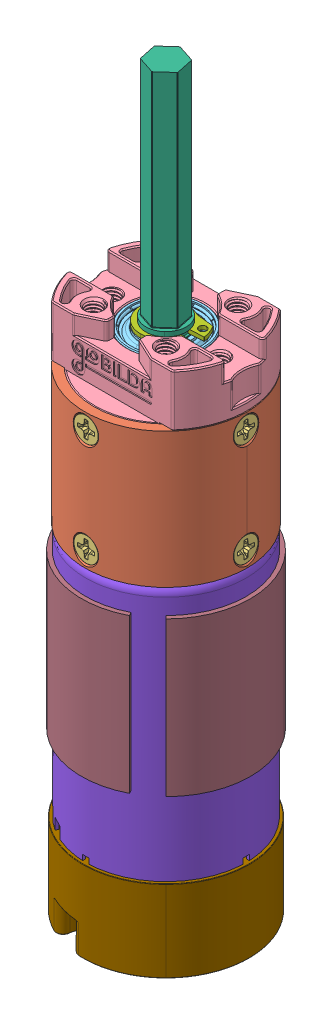
SolidWorks assembly Rex shaft 435rpm motor 45mm length, configuration Default. Lengths in mm.
Overall size (52.29 163.72 52.29).
30 component instances, 15 part files, 0 mates.
Components (placement in the parent):
- 5204-8002-0014 assembly.STEP-1: 5204-8002-0014 assembly.STEP [Default] at origin size (52.29 196.05 52.29)
  - 5104-8002-0014 Simple.STEP-1: 5104-8002-0014 Simple.STEP [Default] at (21.5499 39.1 -25.8711) size (36 121.1 35.97)
    - 5103 Gearbox Base.STEP-1: 5103 Gearbox Base.STEP [Default] at (-58.7206 21.0354 14.7927) size (31.91 5.69 31.91)
    - 5103 Gearbox Barrel (2 stage, simple)_Gear Blank.STEP-1: 5103 Gearbox Barrel (2 stage, simple)_Gear Blank.STEP [Default] at (-58.7206 64.0354 14.7927) x (1 0 0) z (0 -1 0) size (35.97 35.97 30)
    - 5103 Gearbox Barrel Screw (M3 x 8mm length Flat Head)_92010A118.STEP-1: 5103 Gearbox Barrel Screw (M3 x 8mm length Flat Head)_92010A118.STEP [Default] at (-58.7206 24.5354 30.8757) x (0.002439 -0.999997 0) z (0 0 1) size (5.46 5.46 8)
    - 5103 Gearbox Barrel Screw (M3 x 8mm length Flat Head)_92010A118.STEP-2: 5103 Gearbox Barrel Screw (M3 x 8mm length Flat Head)_92010A118.STEP [Default] at (-58.7206 47.5354 30.8757) x (-0.002439 -0.999997 0) z (0 0 1) size (5.46 5.46 8)
    - 5103 Gearbox Barrel Screw (M3 x 8mm length Flat Head)_92010A118.STEP-3: 5103 Gearbox Barrel Screw (M3 x 8mm length Flat Head)_92010A118.STEP [Default] at (-42.6376 24.5354 14.7927) x (0 -0.999997 -0.002439) z (1 0 0) size (5.46 5.46 8)
    - 5103 Gearbox Barrel Screw (M3 x 8mm length Flat Head)_92010A118.STEP-4: 5103 Gearbox Barrel Screw (M3 x 8mm length Flat Head)_92010A118.STEP [Default] at (-58.7206 24.5354 -1.2903) x (-0.002439 -0.999997 0) z (0 0 -1) size (5.46 5.46 8)
    - 5103 Gearbox Barrel Screw (M3 x 8mm length Flat Head)_92010A118.STEP-5: 5103 Gearbox Barrel Screw (M3 x 8mm length Flat Head)_92010A118.STEP [Default] at (-74.8037 24.5354 14.7927) x (0 -0.999997 0.002439) z (-1 0 0) size (5.46 5.46 8)
    - 5103 Gearbox Barrel Screw (M3 x 8mm length Flat Head)_92010A118.STEP-6: 5103 Gearbox Barrel Screw (M3 x 8mm length Flat Head)_92010A118.STEP [Default] at (-42.6376 47.5354 14.7927) x (0 -0.999997 0.002439) z (1 0 0) size (5.46 5.46 8)
    - 5103 Gearbox Barrel Screw (M3 x 8mm length Flat Head)_92010A118.STEP-7: 5103 Gearbox Barrel Screw (M3 x 8mm length Flat Head)_92010A118.STEP [Default] at (-58.7206 47.5354 -1.2903) x (0.002439 -0.999997 0) z (0 0 -1) size (5.46 5.46 8)
    - 5103 Gearbox Barrel Screw (M3 x 8mm length Flat Head)_92010A118.STEP-8: 5103 Gearbox Barrel Screw (M3 x 8mm length Flat Head)_92010A118.STEP [Default] at (-74.8037 47.5354 14.7927) x (0 -0.999997 -0.002439) z (-1 0 0) size (5.46 5.46 8)
    - 5103 Gearbox Face.STEP-1: 5103 Gearbox Face.STEP [Default] at (-58.7206 45.5354 14.7927) size (36 17.1 31.91)
    - 5103 Gearbox Bearing.STEP-1: 5103 Gearbox Bearing.STEP [Default] at (-58.7206 53.6354 14.7927) size (17 5 17)
    - 5103 Gearbox Bearing.STEP-2: 5103 Gearbox Bearing.STEP [Default] at (-58.7206 45.5354 14.7927) size (17 5 17)
    - 5103 Gearbox Shaft (79.5mm Length, Simple).STEP-1: 5103 Gearbox Shaft (79.5mm Length, Simple).STEP [Default] at (-58.7206 42.1754 14.7927) x (0.74423 0 -0.667923) z (0.667923 0 0.74423) size (8.97 96.6 8.97)
    - 5103 Gearbox Snap Ring.STEP-1: 5103 Gearbox Snap Ring.STEP [Default] at (-58.7206 58.7104 14.7927) x (0 1 0) z (0 0 1) size (0.85 13.06 10.66)
  - 5000-0002-0001 body.step-1: 5000-0002-0001 body.step [Default] at (-37.1707 3.4854 -11.0784) size (35.61 61.8 35.61)
  - 5000-0001-0001 encoder cap.STEP-1: 5000-0001-0001 encoder cap.STEP [Default] at (-37.1707 -14.6146 -11.0784) x (0.707107 0 -0.707107) z (0 -1 0) size (36.9 36.9 18.3)
  - 5000-0001-0001 encoder cap screw_90190A075.STEP-1: 5000-0001-0001 encoder cap screw_90190A075.STEP [Default] at (-33.0775 -8.1646 -26.1474) x (0.882398 0 0.470504) z (0 -1 0) size (3.33 3.33 7.86)
  - 5000-0001-0001 encoder pin housing.STEP-1: 5000-0001-0001 encoder pin housing.STEP [Default] at (-44.0085 -0.9746 -21.9467) x (0.707107 0 -0.707107) z (-0.707107 0 -0.707107) size (12.3 7.19 6.3)
  - 5000-0001-0001 encoder pins_MalePinHeader_1X2.STEP-1: 5000-0001-0001 encoder pins_MalePinHeader_1X2.STEP [Default] at (-43.4569 1.2544 -23.1912) x (0.707107 0 -0.707107) z (0 -1 0) size (3.18 0.64 4.27)
  - 5000-0001-0001 motor shield.STEP-1: 5000-0001-0001 motor shield.STEP [Default] at (-37.1707 54.6354 -11.0784) x (0.808104 0 -0.58904) z (0 -1 0) size (37.5 37.27 34.15)
  - 5000-0001-0001 encoder cap screw_90190A075.STEP-2: 5000-0001-0001 encoder cap screw_90190A075.STEP [Default] at (-41.264 -8.1646 3.9905) x (0.882398 0 0.470504) z (0 -1 0) size (3.33 3.33 7.86)
  - 5000-0001-0001 encoder pins_MalePinHeader_1X2.STEP-2: 5000-0001-0001 encoder pins_MalePinHeader_1X2.STEP [Default] at (-47.049 1.2544 -19.5991) x (0.707107 0 -0.707107) z (0 -1 0) size (3.18 0.64 4.27)
  - 5000-0002-0117 motor shaft.STEP-1: 5000-0002-0117 motor shaft.STEP [Default] at (-37.1707 59.4854 -11.0784) size (3.26 12.45 3.14)
  - 5103 Gearbox Base Mounting Screw M3 x 5mm length SHCS)_91290A110.STEP-1: 5103 Gearbox Base Mounting Screw M3 x 5mm length SHCS)_91290A110.STEP [Default] at (-46.0096 57.2554 -2.2396) x (0.056382 0 0.998409) z (0 -1 0) size (5.5 5.5 8.01)
  - 5103 Gearbox Base Mounting Screw M3 x 5mm length SHCS)_91290A110.STEP-2: 5103 Gearbox Base Mounting Screw M3 x 5mm length SHCS)_91290A110.STEP [Default] at (-28.3319 57.2554 -2.2396) x (0.998409 0 -0.056382) z (0 -1 0) size (5.5 5.5 8.01)
  - 5103 Gearbox Base Mounting Screw M3 x 5mm length SHCS)_91290A110.STEP-3: 5103 Gearbox Base Mounting Screw M3 x 5mm length SHCS)_91290A110.STEP [Default] at (-28.3319 57.2554 -19.9173) x (-0.056382 0 -0.998409) z (0 -1 0) size (5.5 5.5 8.01)
  - 5103 Gearbox Base Mounting Screw M3 x 5mm length SHCS)_91290A110.STEP-4: 5103 Gearbox Base Mounting Screw M3 x 5mm length SHCS)_91290A110.STEP [Default] at (-46.0096 57.2554 -19.9173) x (-0.998409 0 0.056382) z (0 -1 0) size (5.5 5.5 8.01)
